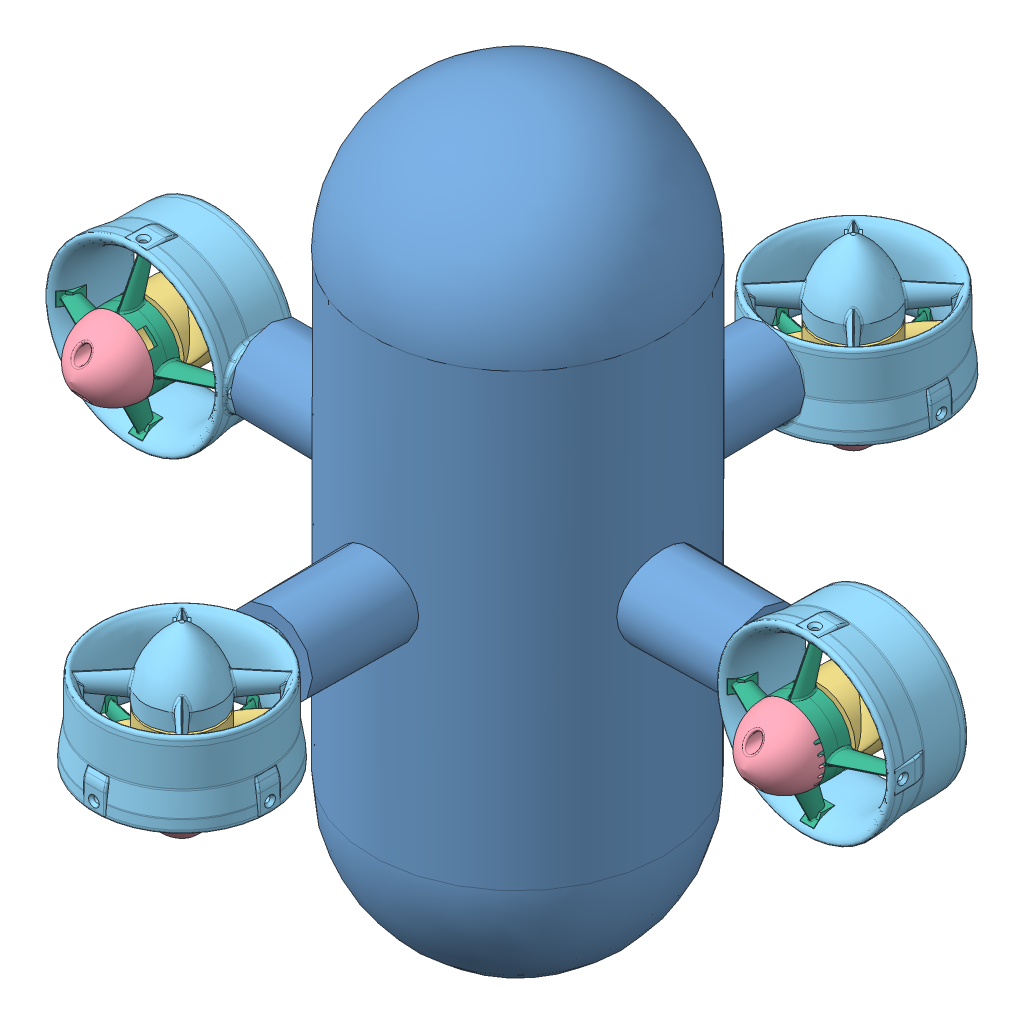
SolidWorks assembly ROV, configuration Default. Lengths in mm.
Overall size (464.61 406.66 464.61).
30 component instances, 7 part files, 14 mates.
Components (placement in the parent):
- ROV-1: ROV [Default] at (196.1344 164.7508 186.8979) size (270 406.66 270)
- watec902H-1: watec902H [Default] at (196.1344 306.3308 161.3979) size (46.8 36.5 58.1)
- T100-THRUSTER-R1 v6.step-1: T100-THRUSTER-R1 v6.step [Default] at (380.1344 164.7508 192.1497) x (0 1 0) z (0 0 1) size (157.85 97.3 100.86)
  - T100-THRUSTER-R1_1.step-1: T100-THRUSTER-R1_1.step [Default] at origin size (157.85 97.3 100.86)
    - Prop (Rev).step-1: Prop (Rev).step [Default] at origin size (59 69.35 19.07) (hidden)
    - Prop.step-1: Prop.step [Default] at origin size (58.99 69.35 19.07)
    - Back.step-1: Back.step [Default] at origin size (40 40 25.4)
    - Main.step-1: Main.step [Default] at origin size (96.61 97.3 67.18)
    - Support.step-1: Support.step [Default] at origin size (87.65 87.65 22.12)
- T100-THRUSTER-R1 v6.step-2: T100-THRUSTER-R1 v6.step [Default] at (12.1344 164.7508 192.1497) x (0 -1 0) z (0 0 1) size (157.85 97.3 100.86)
  - T100-THRUSTER-R1_1.step-1: T100-THRUSTER-R1_1.step [Default] at origin size (157.85 97.3 100.86)
    - Prop (Rev).step-1: Prop (Rev).step [Default] at origin size (59 69.35 19.07) (hidden)
    - Prop.step-1: Prop.step [Default] at origin size (58.99 69.35 19.07)
    - Back.step-1: Back.step [Default] at origin size (40 40 25.4)
    - Main.step-1: Main.step [Default] at origin size (96.61 97.3 67.18)
    - Support.step-1: Support.step [Default] at origin size (87.65 87.65 22.12)
- T100-THRUSTER-R1 v6.step-3: T100-THRUSTER-R1 v6.step [Default] at (196.1344 159.499 2.8979) x (1 0 0) z (0 -1 0) size (157.85 97.3 100.86)
  - T100-THRUSTER-R1_1.step-1: T100-THRUSTER-R1_1.step [Default] at origin size (157.85 97.3 100.86)
    - Prop (Rev).step-1: Prop (Rev).step [Default] at origin size (59 69.35 19.07) (hidden)
    - Prop.step-1: Prop.step [Default] at origin size (58.99 69.35 19.07)
    - Back.step-1: Back.step [Default] at origin size (40 40 25.4)
    - Main.step-1: Main.step [Default] at origin size (96.61 97.3 67.18)
    - Support.step-1: Support.step [Default] at origin size (87.65 87.65 22.12)
- T100-THRUSTER-R1 v6.step-4: T100-THRUSTER-R1 v6.step [Default] at (196.1344 159.499 370.8979) x (-1 0 0) z (0 -1 0) size (157.85 97.3 100.86)
  - T100-THRUSTER-R1_1.step-1: T100-THRUSTER-R1_1.step [Default] at origin size (157.85 97.3 100.86)
    - Prop (Rev).step-1: Prop (Rev).step [Default] at origin size (59 69.35 19.07) (hidden)
    - Prop.step-1: Prop.step [Default] at origin size (58.99 69.35 19.07)
    - Back.step-1: Back.step [Default] at origin size (40 40 25.4)
    - Main.step-1: Main.step [Default] at origin size (96.61 97.3 67.18)
    - Support.step-1: Support.step [Default] at origin size (87.65 87.65 22.12)
Mates (geometry in assembly coordinates):
- Coincident1: coincident anti-aligned: plane of ROV-1 through (331.1344 164.7508 186.8979) normal (1 0 0); plane of T100-THRUSTER-R1 v6.step-1/T100-THRUSTER-R1_1.step-1/Main.step-1 through (331.1344 164.7508 186.8979) normal (-1 0 0)
- Coincident2: coincident anti-aligned: plane of ROV-1 through (196.1344 164.7508 321.8979) normal (0 0 1); plane of T100-THRUSTER-R1 v6.step-4/T100-THRUSTER-R1_1.step-1/Main.step-1 through (196.1344 164.7508 321.8979) normal (0 0 -1)
- Coincident3: coincident anti-aligned: plane of ROV-1 through (61.1344 164.7508 186.8979) normal (-1 0 0); plane of T100-THRUSTER-R1 v6.step-2/T100-THRUSTER-R1_1.step-1/Main.step-1 through (61.1344 164.7508 186.8979) normal (1 0 0)
- Coincident4: coincident anti-aligned: plane of ROV-1 through (196.1344 164.7508 51.8979) normal (0 0 -1); plane of T100-THRUSTER-R1 v6.step-3/T100-THRUSTER-R1_1.step-1/Main.step-1 through (196.1344 164.7508 51.8979) normal (0 0 1)
- Parallel1: parallel anti-aligned: line of ROV-1 through (196.1344 41.4208 186.8979) axis (0 1 0); line of ? through (196.1344 183.0478 370.8979) axis (0 -1 0)
- Parallel2: parallel anti-aligned: line of ROV-1 through (196.1344 41.4208 186.8979) axis (0 1 0); line of ? through (196.1344 183.0478 2.8979) axis (0 -1 0)
- Parallel3: parallel aligned: line of ROV-1 through (196.1344 164.7508 321.8979) axis (0 0 -1); line of T100-THRUSTER-R1 v6.step-2/T100-THRUSTER-R1_1.step-1/Prop.step-1 through (12.1344 164.7508 205.7692) axis (0 0 -1)
- Parallel4: parallel aligned: line of ROV-1 through (196.1344 164.7508 321.8979) axis (0 0 -1); line of T100-THRUSTER-R1 v6.step-1/T100-THRUSTER-R1_1.step-1/Prop.step-1 through (380.1344 164.7508 205.7692) axis (0 0 -1)
- Coincident9: coincident anti-aligned: plane of ROV-1 through (196.1344 288.0808 186.8979) normal (0 1 0); plane of watec902H-1 through (196.1344 288.0808 186.8979) normal (0 -1 0)
- Coincident10: coincident aligned: line of ROV-1 through (196.1344 246.0808 186.8979) axis (0 1 0); line of watec902H-1 through (196.1344 318.5808 186.8979) axis (0 1 0)
- Coincident12: coincident anti-aligned: line of ROV-1 through (331.1344 164.7508 186.8979) axis (-1 0 0); line of ? through (325.4903 164.7508 186.8979) axis (1 0 0)
- Coincident13: coincident aligned: line of ROV-1 through (196.1344 164.7508 110.1271) axis (0 0 -1); line of T100-THRUSTER-R1 v6.step-3/T100-THRUSTER-R1_1.step-1/Main.step-1 through (196.1344 164.7508 56.0167) axis (0 0 -1)
- Coincident14: coincident anti-aligned: line of ROV-1 through (196.1344 164.7508 321.8979) axis (0 0 -1); line of ? through (196.1344 164.7508 316.2538) axis (0 0 1)
- Coincident15: coincident aligned: line of ROV-1 through (116.1344 164.7508 186.8979) axis (-1 0 0); line of ? through (66.7785 164.7508 186.8979) axis (-1 0 0)
